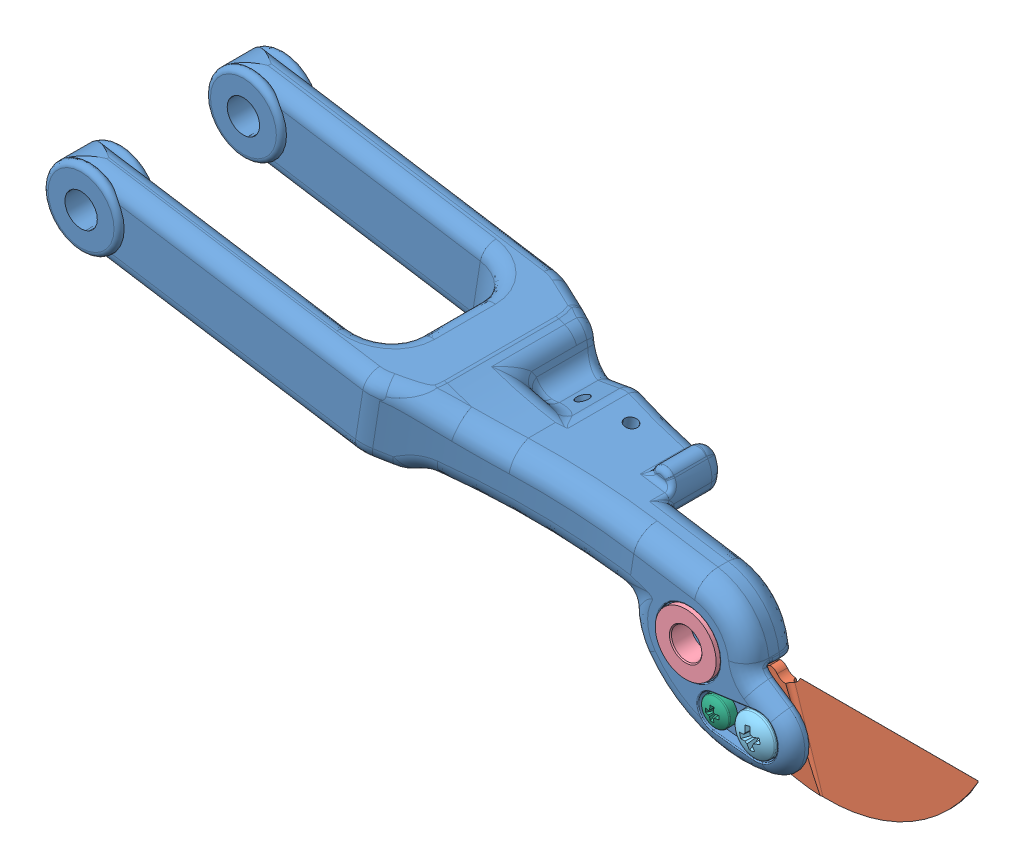
SolidWorks assembly Assieme_PORTALAMA_COMPR-TRAZ, configuration Default. Lengths in mm.
Overall size (170.01 48.69 40).
9 component instances, 7 part files, 14 mates.
Components (placement in the parent):
- PORTALAMA specchiato_COMPR-TRAZ-1: PORTALAMA specchiato_COMPR-TRAZ [Default] at (34.9488 -32.2503 55.8573) size (138.08 48.69 40)
- LAMA5 NUOVA-1: LAMA5 NUOVA [Default] at (48.0839 -41.5236 50.8573) x (0.999898 0.014284 0) z (0 0 1) size (52.01 17.5 2.12)
- hex thin nut chamfered gradeab_isEDEEEEo-4: hex thin nut chamfered gradeab_isEDEEEEo [ISO - 4035 - M4 - N] at (48.0839 -41.5236 49.8573) x (0.999492 -0.031877 0) z (0 0 1) size (7 8.08 2.2)
- BOCCOLA_RSONLINE-1: BOCCOLA_RSONLINE [Default] at (34.9488 -32.2503 56.3573) x (0 0 -1) z (-0.166528 -0.986037 0) size (4 12 12)
- BOCCOLA_RSONLINE-2: BOCCOLA_RSONLINE [Default] at (34.9488 -32.2503 45.3573) x (0 0 1) z (0.391952 0.919986 0) size (4 12 12)
- hex thin nut chamfered gradeab_isEDEEEEo-7: hex thin nut chamfered gradeab_isEDEEEEo [ISO - 4035 - M2 - N] at (-0.2058 -19.6931 40.3573) x (0.943396 0.331667 0) z (-0.331667 0.943396 0) size (4 4.62 1.2)
- pan head cross recess screw-4: pan head cross recess screw [ISO 7045 - M4 x 8 - Z - 8N] at (48.0839 -41.5232 57.1573) x (0 0 -1) z (0.974254 0.225454 0) size (11.02 8 8)
- pan head cross recess screw_iso-1: pan head cross recess screw_iso [ISO 7045 - M3 x 10 - Z - 10N] at (40.0839 -41.6379 56.4573) x (0 0 -1) z (0.99999 0.004568 0) size (9.35 5.6 5.6)
- hex thin nut chamfered gradeab_iso-1: hex thin nut chamfered gradeab_iso [ISO - 4035 - M3 - N] at (40.0839 -41.6379 49.8573) x (0.820804 0.571211 0) z (0 0 1) size (5.5 6.35 1.8)
Mates (geometry in assembly coordinates):
- Concentrico8: concentric anti-aligned: cylinder of PORTALAMA specchiato_COMPR-TRAZ-1 through (34.9488 -32.2503 45.8573) axis (0 0 1) radius 4.25; cylinder of BOCCOLA_RSONLINE-1 through (34.9488 -32.2503 56.3573) axis (0 0 -1) radius 4
- Coincidente12: coincident anti-aligned: plane of PORTALAMA specchiato_COMPR-TRAZ-1 through (34.9488 -32.2503 55.3573) normal (0 0 1); plane of BOCCOLA_RSONLINE-1 through (38.893 -32.9164 55.3573) normal (0 0 -1)
- Concentrico9: concentric aligned: cylinder of PORTALAMA specchiato_COMPR-TRAZ-1 through (34.9488 -32.2503 45.8573) axis (0 0 1) radius 4.25; cylinder of BOCCOLA_RSONLINE-2 through (34.9488 -32.2503 45.3573) axis (0 0 1) radius 4
- Coincidente13: coincident anti-aligned: plane of PORTALAMA specchiato_COMPR-TRAZ-1 through (34.9488 -32.2503 46.3573) normal (0 0 -1); plane of BOCCOLA_RSONLINE-2 through (38.6288 -33.8181 46.3573) normal (0 0 1)
- Concentrico18: concentric anti-aligned: cylinder of PORTALAMA specchiato_COMPR-TRAZ-1 through (-3.025 -11.6743 40.3573) axis (0.331667 -0.943396 0) radius 1.25; cylinder of hex thin nut chamfered gradeab_isEDEEEEo-7 through (0.1922 -20.8252 40.3573) axis (-0.331667 0.943396 0) radius 0.8
- Coincidente42: coincident anti-aligned: plane of PORTALAMA specchiato_COMPR-TRAZ-1 through (27.1527 -10.0748 55.8573) normal (0.331667 -0.943396 0); plane of hex thin nut chamfered gradeab_isEDEEEEo-7 through (-0.2058 -19.6931 38.0479) normal (-0.331667 0.943396 0)
- Parallelo1: parallel anti-aligned: plane of hex thin nut chamfered gradeab_isEDEEEEo-7 through (2.079 -20.1619 39.2026) normal (0.943396 0.331667 0); plane of PORTALAMA specchiato_COMPR-TRAZ-1 through (1.9168 -18.9469 41.8083) normal (-0.943396 -0.331667 0)
- Coincidente44: coincident anti-aligned: plane of LAMA5 NUOVA-1 through (48.0839 -41.5236 49.8573) normal (0 0 -1); plane of hex thin nut chamfered gradeab_iso-4 through (48.2128 -37.4842 49.8573) normal (0 0 1)
- Concentrico23: concentric anti-aligned: cylinder of PORTALAMA specchiato_COMPR-TRAZ-1 through (48.0839 -41.5232 55.8573) axis (0 0 -1) radius 2.25; cylinder of pan head cross recess screw-4 through (48.0839 -41.5232 82.5573) axis (0 0 1) radius 2
- Coincidente47: coincident anti-aligned: plane of PORTALAMA specchiato_COMPR-TRAZ-1 through (40.0839 -41.6379 54.0573) normal (0 0 1); plane of pan head cross recess screw-4 through (47.633 -39.5747 54.0573) normal (0 0 -1)
- Concentrico24: concentric anti-aligned: cylinder of PORTALAMA specchiato_COMPR-TRAZ-1 through (40.0839 -41.6379 55.8573) axis (0 0 -1) radius 1.75; cylinder of pan head cross recess screw_iso-1 through (40.0839 -41.6379 81.8573) axis (0 0 1) radius 1.5
- Coincidente48: coincident anti-aligned: plane of PORTALAMA specchiato_COMPR-TRAZ-1 through (40.0839 -41.6379 54.0573) normal (0 0 1); plane of pan head cross recess screw_iso-1 through (40.0771 -40.1379 54.0573) normal (0 0 -1)
- Concentrico25: concentric aligned: cylinder of pan head cross recess screw_iso-1 through (40.0839 -41.6379 81.8573) axis (0 0 1) radius 1.5; cylinder of hex thin nut chamfered gradeab_iso-1 through (40.0839 -41.6379 48.0573) axis (0 0 1) radius 1.25
- Coincidente49: coincident anti-aligned: plane of LAMA5 NUOVA-1 through (48.0839 -41.5236 49.8573) normal (0 0 -1); plane of hex thin nut chamfered gradeab_iso-1 through (38.2701 -39.0315 49.8573) normal (0 0 1)
